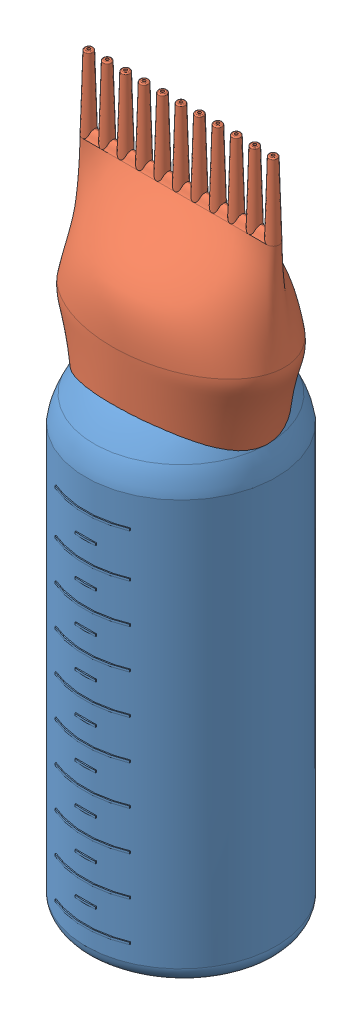
SolidWorks assembly Bottle_bottlecap_assembly, configuration Default. Lengths in mm.
Overall size (50.32 169 46.89).
2 component instances, 2 part files, 2 mates.
Components (placement in the parent):
- Bottle-2: Bottle [Default<As Machined>] at (-11.6532 -64.9615 134.0241) size (46.89 133.62 46.89)
- BottleCap-2: BottleCap [Default] at (-11.6532 43.0385 134.0241) x (1 0 -0.000354) z (0.000354 0 1) size (50.31 62.15 35.13)
Mates (geometry in assembly coordinates):
- Concentric1: concentric anti-aligned: cylinder of Bottle-2 through (-11.6532 68.4385 134.0241) axis (0 -1 0) radius 11; cylinder of BottleCap-2 through (-11.6532 65.4385 134.0241) axis (0 1 0) radius 6.5
- Coincident1: coincident anti-aligned: plane of Bottle-2 through (-11.6532 68.4385 134.0241) normal (0 1 0); plane of BottleCap-2 through (-11.6532 68.4385 134.0241) normal (0 -1 0)
